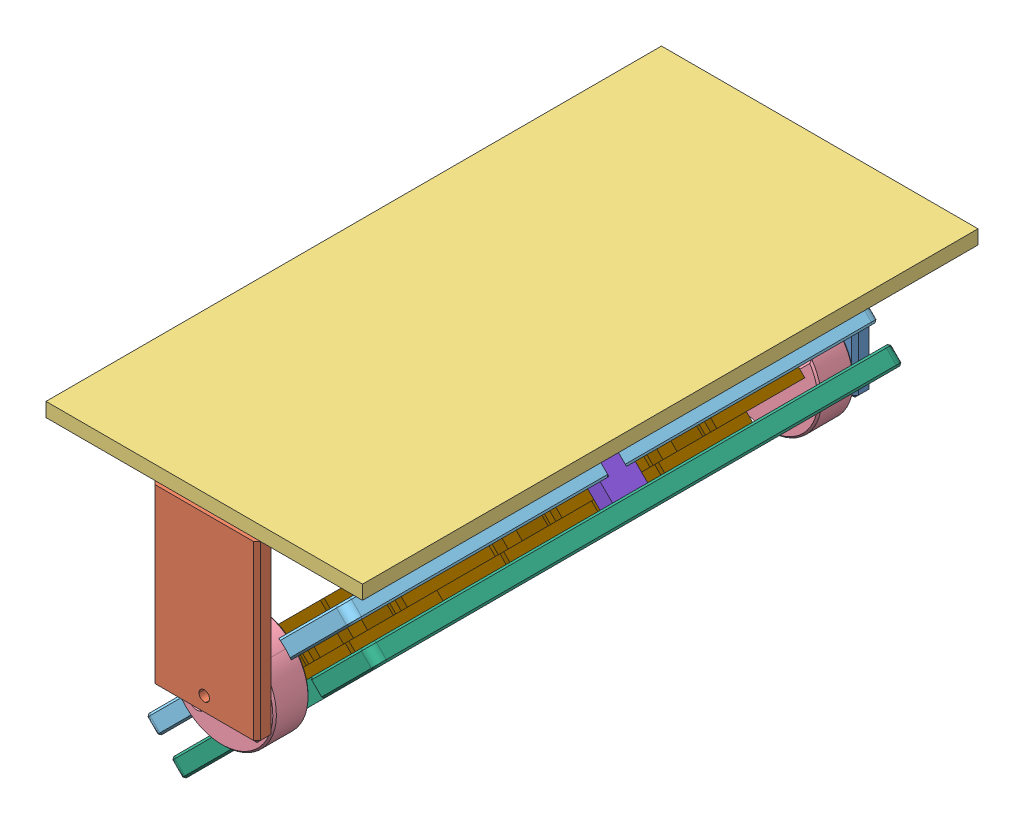
SolidWorks assembly posage insertion composant 2, configuration Default. Lengths in mm.
Overall size (180 174.25 350).
22 component instances, 9 part files, 0 mates.
Components (placement in the parent):
- posage insertion composant 2.STEP-1: posage insertion composant 2.STEP [Défaut] at origin size (180 174.25 350)
  - conception3.STEP.STEP-1: conception3.STEP.STEP [Défaut] at origin size (180 174.25 350)
    - LD.STEP.STEP-1: LD.STEP.STEP [Défaut] at (-44.7339 -26.7122 65) size (60 100 10)
    - LG.STEP.STEP-1: LG.STEP.STEP [Défaut] at (-44.7339 -26.7122 405) size (60 100 10)
    - SEMELLE INF.STEP.STEP-1: SEMELLE INF.STEP.STEP [Défaut] at (-104.7339 83.2878 415) x (0 0 -1) z (0 -1 0) size (350 180 10)
    - roue de position.STEP.STEP-1: roue de position.STEP.STEP [Défaut] at (-14.7339 -16.7122 75) x (0.707107 0.707107 0) z (0 0 1) size (60 60 20)
    - roue de position.STEP.STEP-2: roue de position.STEP.STEP [Défaut] at (-14.7339 -16.7122 405) x (0.707107 0.707107 0) z (0 0 -1) size (60 60 20)
    - support pi_ce.STEP.STEP-1: support pi_ce.STEP.STEP [Défaut] at (38.2991 43.3919 90) x (0 0 1) z (0.707107 -0.707107 0) size (300 160 10)
    - cache support pi_ce.STEP.STEP-1: cache support pi_ce.STEP.STEP [Défaut] at (59.5123 22.1787 390) x (0 0 -1) z (-0.707107 0.707107 0) size (300 160 10)
    - charni_re.STEP.STEP-1: charni_re.STEP.STEP [Défaut] at (-60.6958 -83.8873 160) x (0.707107 0.707107 0) z (0 0 1) size (10 10 10)
    - charni_re.STEP.STEP-2: charni_re.STEP.STEP [Défaut] at (-60.6958 -69.7452 320) x (-0.707107 -0.707107 0) z (0 0 1) size (10 10 10)
    - charni_re.STEP.STEP-3: charni_re.STEP.STEP [Défaut] at (-60.6958 -83.8873 310) x (0.707107 0.707107 0) z (0 0 1) size (10 10 10)
    - charni_re.STEP.STEP-4: charni_re.STEP.STEP [Défaut] at (-60.6958 -83.8873 140) x (0.707107 0.707107 0) z (0 0 1) size (10 10 10)
    - charni_re.STEP.STEP-5: charni_re.STEP.STEP [Défaut] at (-60.6958 -69.7452 150) x (-0.707107 -0.707107 0) z (0 0 1) size (10 10 10)
    - charni_re.STEP.STEP-6: charni_re.STEP.STEP [Défaut] at (-60.6958 -83.8873 330) x (0.707107 0.707107 0) z (0 0 1) size (10 10 10)
    - accroche.STEP.STEP-1: accroche.STEP.STEP [Défaut] at (45.3702 22.1787 230) x (0 0 1) z (-0.707107 0.707107 0) size (20 10 20)
    - mod_le.STEP.STEP-1: mod_le.STEP.STEP [Défaut] at (34.7636 18.6431 299) x (-0.707107 -0.707107 0) z (0 0 -1) size (50 35 58)
    - mod_le.STEP.STEP-2: mod_le.STEP.STEP [Défaut] at (-14.7339 -30.8543 299) x (-0.707107 -0.707107 0) z (0 0 -1) size (50 35 58)
    - mod_le.STEP.STEP-3: mod_le.STEP.STEP [Défaut] at (-14.7339 -30.8543 123) x (-0.707107 -0.707107 0) z (0 0 -1) size (50 35 58)
    - mod_le.STEP.STEP-4: mod_le.STEP.STEP [Défaut] at (34.7636 18.6431 211) x (-0.707107 -0.707107 0) z (0 0 -1) size (50 35 58)
    - mod_le.STEP.STEP-5: mod_le.STEP.STEP [Défaut] at (-14.7339 -30.8543 211) x (-0.707107 -0.707107 0) z (0 0 -1) size (50 35 58)
    - mod_le.STEP.STEP-6: mod_le.STEP.STEP [Défaut] at (34.7636 18.6431 123) x (-0.707107 -0.707107 0) z (0 0 -1) size (50 35 58)
